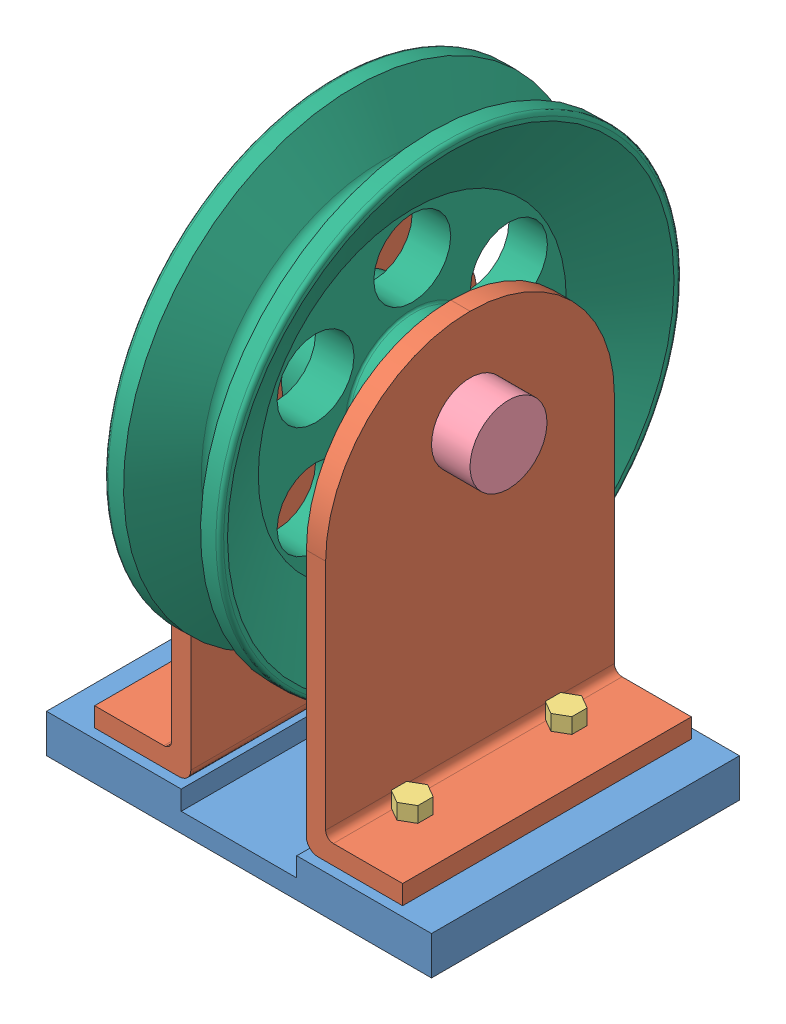
SolidWorks assembly pulley-assembly, configuration Default. Lengths in mm.
Overall size (2540 3821.7 3048).
10 component instances, 6 part files, 26 mates.
Components (placement in the parent):
- Base Plate-1: Base Plate [Default] at (1079.1625 406.2602 2418.7583) size (2540 254 2032)
- Bracket-1: Bracket [Default] at (1460.1625 660.2602 1466.2583) x (0 0 -1) z (1 0 0) size (1905 2724.15 698.5)
- Bracket-2: Bracket [Default] at (698.1625 660.2602 3371.2583) x (0 0 1) z (-1 0 0) size (1905 2724.15 698.5)
- Bolt-1: Bolt [Default] at (444.1625 787.2602 2926.7583) x (0 0 1) z (-1 0 0) size (202.45 355.6 175.33)
- Bolt-2: Bolt [Default] at (1714.1625 787.2602 2926.7583) x (0 0 1) z (-1 0 0) size (202.45 355.6 175.33)
- Bolt-3: Bolt [Default] at (1714.1625 787.2602 1910.7583) x (0 0 1) z (-1 0 0) size (202.45 355.6 175.33)
- Bolt-4: Bolt [Default] at (444.1625 787.2602 1910.7583) x (0 0 -1) z (1 0 0) size (202.45 355.6 175.33)
- Axle-2: Axle [Default] at (571.1625 2692.2602 2418.7583) x (0 0 1) z (0 -1 0) size (670.56 1816.1 609.6)
- Key-2: Key [Default] at (1079.1625 3047.8602 2418.7583) x (1 0 0) z (0 0 -1) size (635 203.2 152.4)
- Pulley-2: Pulley [Default] at (1079.1625 2703.9596 2418.7583) x (0 0 1) z (0 -1 0) size (3048 762 3048)
Mates (geometry in assembly coordinates):
- Coincident1: coincident: plane of Base Plate-1 through (1079.1625 660.2602 2418.7583) normal (0 1 0); plane of Bracket-2 through (63.1625 660.2602 1466.2583) normal (0 -1 0)
- Concentric1: concentric: circle of Base Plate-1; circle of Bracket-2
- Concentric2: concentric: circle of Base Plate-1; circle of Bracket-2
- Coincident4: coincident: plane of Base Plate-1 through (1079.1625 660.2602 2418.7583) normal (0 1 0); plane of Bracket-1 through (2095.1625 660.2602 3371.2583) normal (0 -1 0)
- Concentric3: concentric: circle of Base Plate-1; circle of Bracket-1
- Concentric4: concentric: circle of Base Plate-1; circle of Bracket-1
- Concentric5: concentric: circle of Bracket-1; cylinder of Bolt-2 through (1714.1625 533.2602 2926.7583) axis (0 1 0) radius 63.5
- Concentric6: concentric: circle of Bracket-1; cylinder of Bolt-3 through (1714.1625 533.2602 1910.7583) axis (0 1 0) radius 63.5
- Coincident9: coincident: circle of Bracket-1; plane of Bolt-2 through (1714.1625 787.2602 2926.7583) normal (0 -1 0)
- Coincident10: coincident: circle of Bracket-1; plane of Bolt-3 through (1714.1625 787.2602 1910.7583) normal (0 -1 0)
- Concentric7: concentric: circle of Bracket-2; cylinder of Bolt-1 through (444.1625 533.2602 2926.7583) axis (0 1 0) radius 63.5
- Concentric8: concentric: cylinder of Bracket-2 through (444.1625 787.2602 1910.7583) axis (0 1 0) radius 63.5; cylinder of Bolt-4 through (444.1625 533.2602 1910.7583) axis (0 1 0) radius 63.5
- Coincident12: coincident: circle of Bracket-2; circle of Bolt-1
- Coincident13: coincident: circle of Bracket-2; circle of Bolt-4
- Parallel4: parallel: plane of Base Plate-1 through (1079.1625 406.2602 2418.7583) normal (1 0 0); plane of Bolt-2 through (1714.1625 787.2602 2926.7583) normal (-1 0 0)
- Parallel5: parallel: plane of Base Plate-1 through (1079.1625 406.2602 2418.7583) normal (1 0 0); plane of Bolt-3 through (1714.1625 787.2602 1910.7583) normal (-1 0 0)
- Parallel6: parallel: plane of Base Plate-1 through (1079.1625 406.2602 2418.7583) normal (1 0 0); plane of Bolt-1 through (444.1625 787.2602 2926.7583) normal (-1 0 0)
- Parallel7: parallel: plane of Base Plate-1 through (1079.1625 406.2602 2418.7583) normal (1 0 0); plane of Bolt-4 through (444.1625 787.2602 1910.7583) normal (1 0 0)
- Concentric11: concentric: circle of Bracket-1; circle of Axle-2
- Coincident40: coincident: plane of Axle-2 through (1396.6625 2844.6602 2494.9583) normal (0 0 -1); plane of Key-2 through (1396.6625 2844.6602 2494.9583) normal (0 0 1)
- Coincident41: coincident: plane of Axle-2 through (1396.6625 2844.6602 2342.5583) normal (-1 0 0); plane of Key-2 through (1396.6625 2844.6602 2342.5583) normal (1 0 0)
- Coincident42: coincident: plane of Axle-2 through (571.1625 2844.6602 2418.7583) normal (0 1 0); plane of Key-2 through (1079.1625 2844.6602 2418.7583) normal (0 -1 0)
- Coincident45: coincident: plane of Bracket-2 through (571.1625 3327.2602 1466.2583) normal (-1 0 0); circle of Axle-2
- Coincident49: coincident: plane of Key-2 through (1396.6625 2844.6602 2342.5583) normal (0 0 -1); plane of Pulley-2 through (1460.1625 2946.2602 2342.5583) normal (0 0 1)
- Coincident50: coincident: plane of Key-2 through (1079.1625 3047.8602 2418.7583) normal (0 1 0); plane of Pulley-2 through (1460.1625 3047.8602 2342.5583) normal (0 -1 0)
- Coincident52: coincident: plane of Base Plate-1 through (1079.1625 406.2602 2418.7583) normal (1 0 0); plane of Pulley-2 through (1079.1625 2703.9596 2418.7583) normal (-1 0 0)
